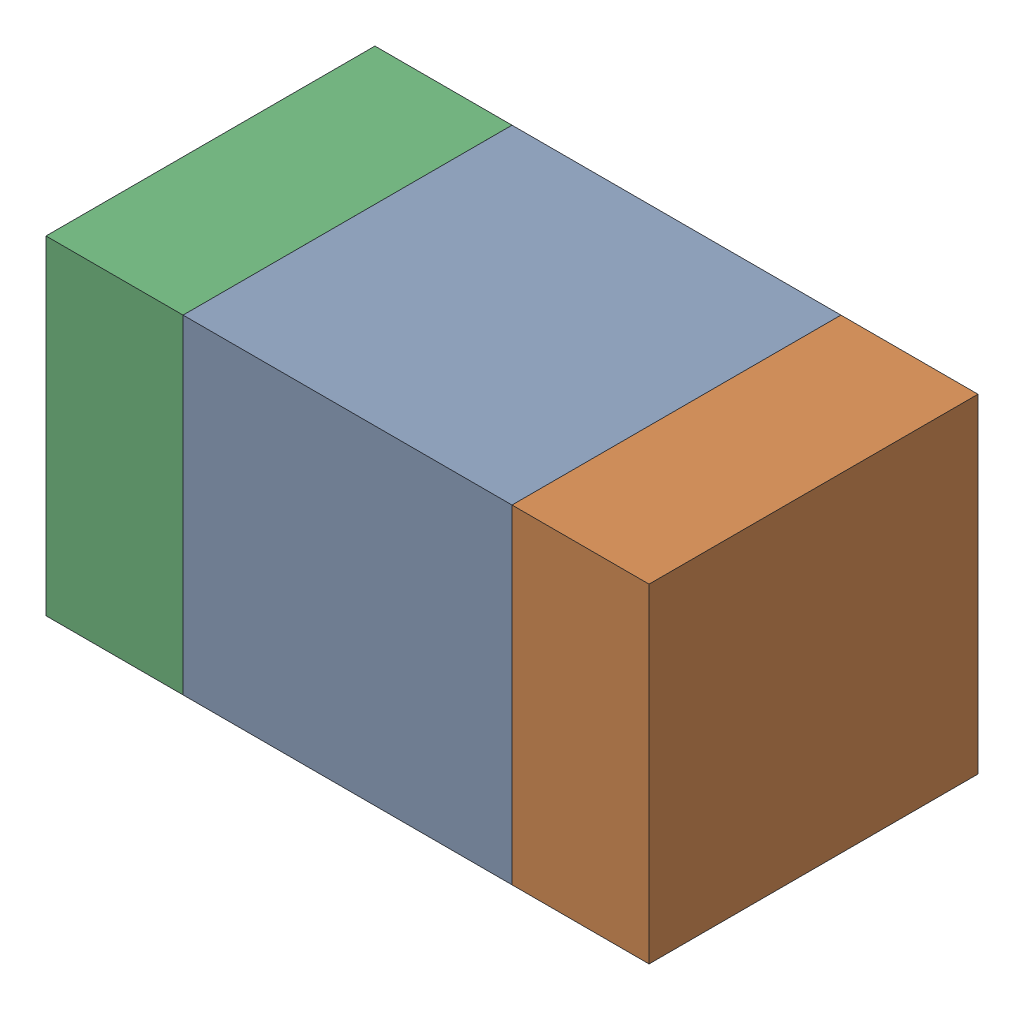
SolidWorks assembly C126_2PCB, configuration Default. Lengths in mm.
Overall size (1.1 0.6 0.6).
6 component instances, 2 part files, 0 mates.
Components (placement in the parent):
- 761606048-1: 761606048 [Default] at (105.8 84.1 0) size (0.6 0.6 0.6)
  - Extruded_9-1: Extruded_9 [Default] at origin size (0.6 0.6 0.6)
- 854785160-1: 854785160 [Default] at (106.225 84.1 0) size (0.25 0.6 0.6)
  - Extruded_19-1: Extruded_19 [Default] at origin size (0.25 0.6 0.6)
- 854785160-2: 854785160 [Default] at (105.375 84.1 0) size (0.25 0.6 0.6)
  - Extruded_19-1: Extruded_19 [Default] at origin size (0.25 0.6 0.6)
